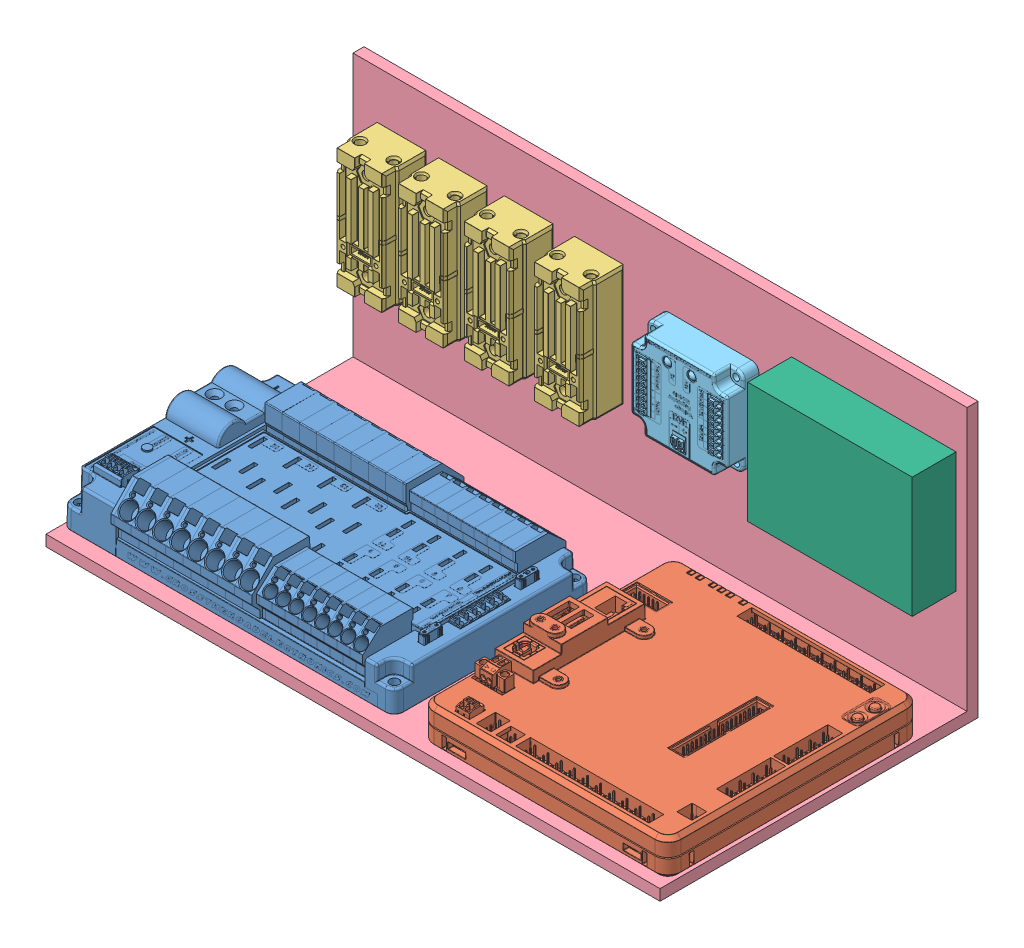
SolidWorks assembly 2 concept(14x10) levels, configuration Default. Lengths in mm.
Overall size (355.6 158.75 184.15).
9 component instances, 6 part files, 25 mates.
Components (placement in the parent):
- PDP-1: PDP [Default] at (-352.4828 246.4376 242.0199) size (192.68 36.15 120.93)
- Roborio-1: Roborio [Default] at (-169.2885 249.4094 230.6446) x (0 0 -1) z (0 1 0) size (146.27 143.19 36.83)
- Speed Controller-1: Speed Controller [Default] at (-425.1986 329.448 146.3852) x (1 0 0) z (0 0 -1) size (30.12 70.11 24.39)
- Speed Controller-2: Speed Controller [Default] at (-389.6386 329.448 146.3852) x (1 0 0) z (0 0 -1) size (30.12 70.11 24.39)
- Speed Controller-3: Speed Controller [Default] at (-351.5386 329.448 146.3852) x (1 0 0) z (0 0 -1) size (30.12 70.11 24.39)
- Speed Controller-4: Speed Controller [Default] at (-310.8986 329.448 146.3852) x (1 0 0) z (0 0 -1) size (30.12 70.11 24.39)
- intial concept poly bent-1: intial concept poly bent [Default] at (-453.2986 233.4074 308.3477) size (355.6 158.75 184.15)
- VRM-2: VRM [Default] at (-245.8917 329.6728 137.679) x (1 0 0) z (0 -1 0) size (56.39 19.92 51.56)
- radio b;ock-2: radio b;ock [Default] at (-199.2986 296.9074 155.9477) x (0 1 0) z (-1 0 0) size (69.85 25.4 95.25)
Mates (geometry in assembly coordinates):
- Coincident1: coincident: plane of Roborio-1 through (-107.6346 239.7574 304.1565) normal (0 1 0); plane of intial concept poly bent-1 through (-453.2986 239.7574 308.3477) normal (0 1 0)
- Coincident2: coincident anti-aligned: plane of PDP-1 through (-260.4586 239.7574 299.4239) normal (0 -1 0); plane of intial concept poly bent-1 through (-453.2986 239.7574 308.3477) normal (0 1 0)
- Distance2: distance = 25.4 mm aligned: plane of PDP-1 through (-444.4956 270.2992 282.9477) normal (0 0 1); plane of intial concept poly bent-1 through (-453.2986 239.7574 308.3477) normal (0 0 1)
- Distance3: distance = 8.8029 mm aligned: plane of PDP-1 through (-444.4956 270.2992 279.8677) normal (-1 0 0); plane of intial concept poly bent-1 through (-453.2986 239.7574 308.3477) normal (-1 0 0)
- Distance4: distance = 12.7 mm: plane of Roborio-1 through (-220.7933 261.8028 295.6477) normal (0 0 -1); plane of intial concept poly bent-1 through (-453.2986 239.7574 308.3477) normal (0 0 1)
- Coincident7: coincident anti-aligned: plane of Speed Controller-4 through (-295.8362 364.373 130.5477) normal (0 0 -1); plane of intial concept poly bent-1 through (-453.2986 392.1574 130.5477) normal (0 0 1)
- Coincident8: coincident anti-aligned: plane of Speed Controller-3 through (-336.4762 364.373 130.5477) normal (0 0 -1); plane of intial concept poly bent-1 through (-453.2986 392.1574 130.5477) normal (0 0 1)
- Coincident9: coincident anti-aligned: plane of Speed Controller-2 through (-374.5762 364.373 130.5477) normal (0 0 -1); plane of intial concept poly bent-1 through (-453.2986 392.1574 130.5477) normal (0 0 1)
- Coincident10: coincident anti-aligned: plane of Speed Controller-1 through (-410.1362 364.373 130.5477) normal (0 0 -1); plane of intial concept poly bent-1 through (-453.2986 392.1574 130.5477) normal (0 0 1)
- Distance5: distance = 25.4 mm aligned: plane of Speed Controller-1 through (-427.8986 315.5574 153.0352) normal (-1 0 0); plane of intial concept poly bent-1 through (-453.2986 239.7574 308.3477) normal (-1 0 0)
- Distance6: distance = 76.2 mm aligned: plane of Speed Controller-1 through (-427.8986 315.9574 153.0352) normal (0 1 0); plane of intial concept poly bent-1 through (-453.2986 392.1574 308.3477) normal (0 1 0)
- Distance7: distance = 76.2 mm aligned: plane of Speed Controller-2 through (-392.3386 315.9574 153.0352) normal (0 1 0); plane of intial concept poly bent-1 through (-453.2986 392.1574 308.3477) normal (0 1 0)
- Distance8: distance = 76.2 mm: plane of Speed Controller-3 through (-351.6986 315.9574 153.0352) normal (0 1 0); line of intial concept poly bent-1 through (-453.2986 392.1574 130.5477) axis (1 0 0)
- Distance10: distance = 76.2 mm aligned: plane of Speed Controller-4 through (-309.7886 315.9574 153.0352) normal (0 1 0); plane of intial concept poly bent-1 through (-453.2986 392.1574 308.3477) normal (0 1 0)
- Distance11: distance = 63.5 mm aligned: plane of Speed Controller-2 through (-389.7986 315.5574 153.0352) normal (-1 0 0); plane of intial concept poly bent-1 through (-453.2986 239.7574 308.3477) normal (-1 0 0)
- Distance12: distance = 101.6 mm aligned: plane of Speed Controller-3 through (-351.6986 315.5574 153.0352) normal (-1 0 0); plane of intial concept poly bent-1 through (-453.2986 239.7574 308.3477) normal (-1 0 0)
- Distance13: distance = 139.7 mm: line of Speed Controller-4 through (-313.5986 315.9574 153.0352) axis (0 0 -1); plane of intial concept poly bent-1 through (-453.2986 239.7574 308.3477) normal (-1 0 0)
- Coincident19: coincident: plane of intial concept poly bent-1 through (-453.2986 392.1574 130.5477) normal (0 0 1); plane of radio b;ock-2 through (-199.2986 296.9074 130.5477) normal (0 0 -1)
- Coincident21: coincident anti-aligned: plane of intial concept poly bent-1 through (-453.2986 392.1574 130.5477) normal (0 0 1); plane of VRM-2 through (-222.5474 349.22 130.5477) normal (0 0 -1)
- Distance16: distance = 127 mm aligned: plane of VRM-2 through (-224.6986 338.6799 150.4723) normal (1 0 0); plane of intial concept poly bent-1 through (-97.6986 239.7574 308.3477) normal (1 0 0)
- Distance17: distance = 50.8 mm aligned: plane of VRM-2 through (-265.0881 341.3574 150.4723) normal (0 1 0); plane of intial concept poly bent-1 through (-453.2986 392.1574 308.3477) normal (0 1 0)
- Parallel1: parallel: line of intial concept poly bent-1 through (-453.2986 392.1574 130.5477) axis (1 0 0); plane of radio b;ock-2 through (-199.2986 366.7574 130.5477) normal (0 1 0)
- Distance18: distance = 6.35 mm: plane of radio b;ock-2 through (-104.0486 296.9074 130.5477) normal (1 0 0); plane of intial concept poly bent-1 through (-97.6986 239.7574 308.3477) normal (1 0 0)
- Distance19: distance = 25.4 mm aligned: plane of radio b;ock-2 through (-199.2986 366.7574 130.5477) normal (0 1 0); plane of intial concept poly bent-1 through (-453.2986 392.1574 308.3477) normal (0 1 0)
- Coincident24: coincident anti-aligned: plane of Roborio-1 through (-97.6986 241.9896 298.7186) normal (-1 0 0); plane of intial concept poly bent-1 through (-97.6986 239.7574 308.3477) normal (1 0 0)
